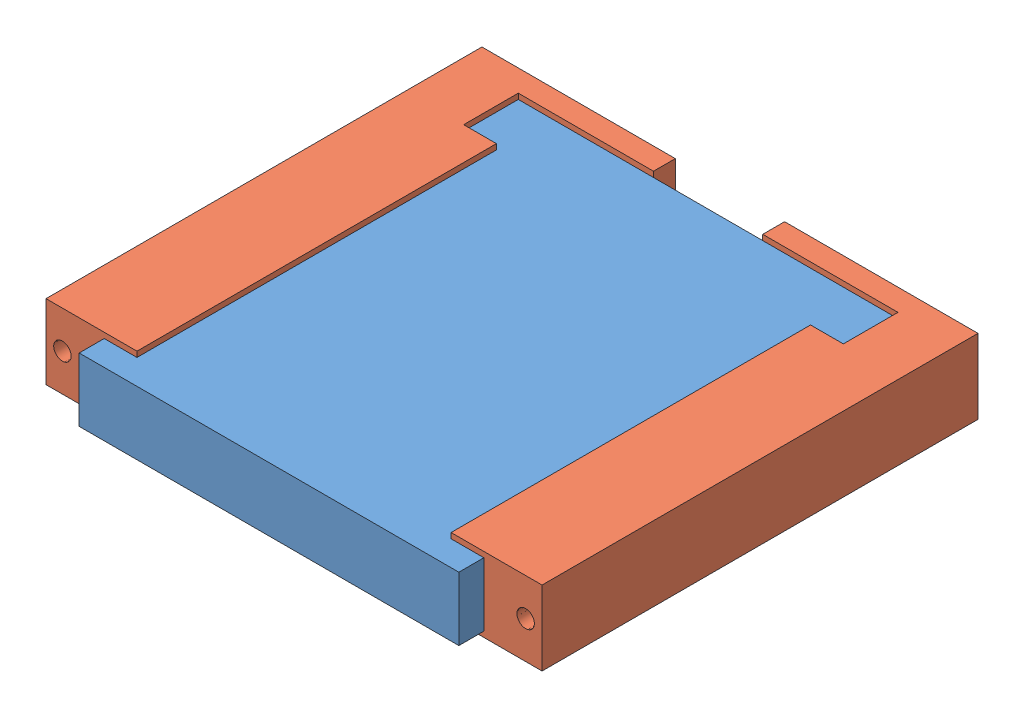
SolidWorks assembly BraceMagVertSolid_draft6_20160427, configuration Default. Lengths in mm.
Overall size (45.4 6.82 42.19).
2 component instances, 2 part files, 3 mates.
Components (placement in the parent):
- MagnetActual_draf6_20160424-1: MagnetActual_draf6_20160424 [Default] at (-195.3725 -16.2397 114.3575) size (34.75 5.82 40.19)
- VertMagBraceSolid_draft3_20160427-1: VertMagBraceSolid_draft3_20160427 [Default] at (-155.2965 -9.9197 112.0675) x (0 0 -1) z (0 1 0) size (39.9 45.4 6.82)
Mates (geometry in assembly coordinates):
- Coincident6: coincident anti-aligned: plane of MagnetActual_draf6_20160424-1 through (-195.3725 -10.4197 74.1675) normal (0 0 -1); plane of VertMagBraceSolid_draft3_20160427-1 through (-155.2965 -9.9197 74.1675) normal (0 0 1)
- Coincident7: coincident anti-aligned: plane of MagnetActual_draf6_20160424-1 through (-195.3725 -10.4197 114.3575) normal (-1 0 0); plane of VertMagBraceSolid_draft3_20160427-1 through (-195.3725 -16.2397 36.7545) normal (1 0 0)
- Coincident8: coincident anti-aligned: plane of MagnetActual_draf6_20160424-1 through (-195.3725 -10.4197 114.3575) normal (0 1 0); plane of VertMagBraceSolid_draft3_20160427-1 through (-192.3725 -10.4197 36.7545) normal (0 -1 0)
